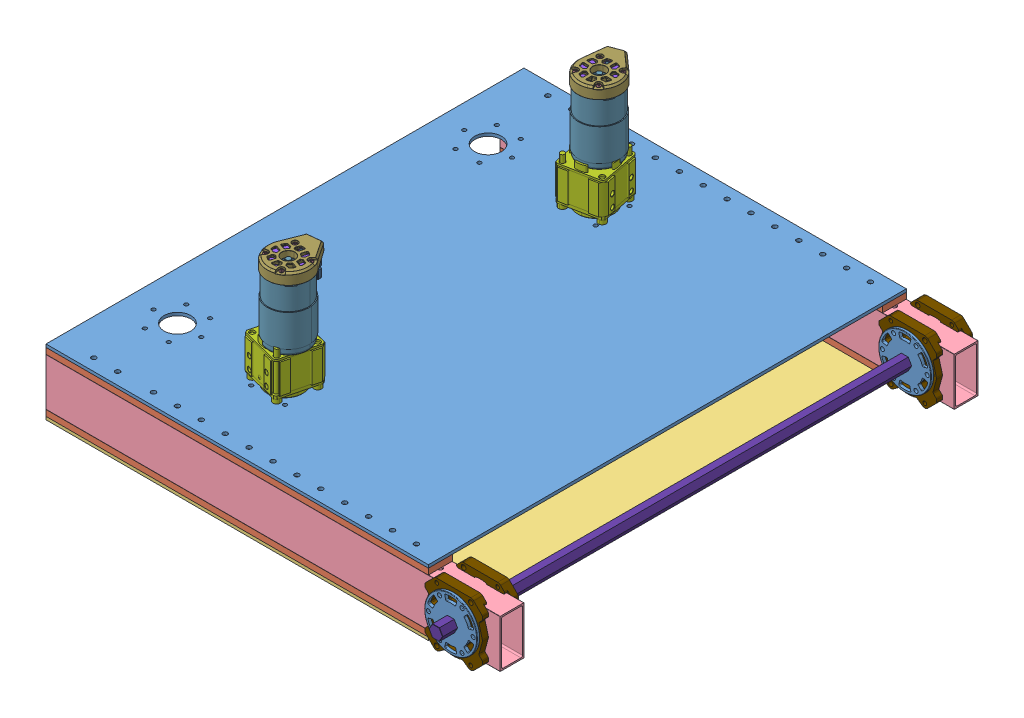
SolidWorks assembly bracket top down new shooter assembly, configuration Default. Lengths in mm.
Overall size (482.6 222.05 558.8).
61 component instances, 19 part files, 71 mates.
Components (placement in the parent):
- ShooterPlate5-1: ShooterPlate5 [Default] at (-92.3523 325.8959 643.1212) size (406.4 3.17 508)
- ThickStick-3: ThickStick [Default] at (-92.3523 262.3959 643.1212) size (406.4 6.35 25.4)
- ThickStick-1: ThickStick [Default] at (-92.3523 319.5459 643.1212) size (406.4 6.35 25.4)
- ThickStick-2: ThickStick [Default] at (-92.3523 262.3959 160.5212) size (406.4 6.35 25.4)
- ThickStick-4: ThickStick [Default] at (-92.3523 319.5459 160.5212) size (406.4 6.35 25.4)
- ShooterPlate4-1: ShooterPlate4 [Default] at (-257.4523 259.2209 643.1212) size (406.4 3.17 508)
- side-1: side [Default] at (364.8477 294.1459 147.8212) x (0 0 1) z (-1 0 0) size (25.4 50.8 482.6)
- side-2: side [Default] at (364.8477 294.1459 630.4212) x (0 0 1) z (-1 0 0) size (25.4 50.8 482.6)
- 4in hex stealth wheel-2: 4in hex stealth wheel [Default] at (72.733 290.5093 554.2466) x (0 -1 0) z (-0.5 0 0.866025) size (25.4 101.6 101.6)
  - 4in Wheel Intergreated Hub 500 HEX.STEP-1: 4in Wheel Intergreated Hub 500 HEX.STEP [Default] at origin size (25.4 92.71 92.71)
  - 4in Tread.STEP-1: 4in Tread.STEP [Default] at origin size (25.4 101.6 101.6)
- 4in hex stealth wheel-3: 4in hex stealth wheel [Default] at (72.7256 290.5093 224.0405) x (0 -1 0) z (0.194202 0 0.980962) size (25.4 101.6 101.6)
  - 4in Wheel Intergreated Hub 500 HEX.STEP-1: 4in Wheel Intergreated Hub 500 HEX.STEP [Default] at origin size (25.4 92.71 92.71)
  - 4in Tread.STEP-1: 4in Tread.STEP [Default] at origin size (25.4 101.6 101.6)
- 4-1 Banebots-1: 4-1 Banebots [Default] at (72.7475 371.6159 224.0202) x (-0.194202 0 -0.980962) z (0 -1 0) size (47.62 47.62 76.19)
- 4-1 Banebots-2: 4-1 Banebots [Default] at (72.7467 371.6159 554.2209) x (-0.969356 0 -0.245662) z (0 -1 0) size (47.62 47.62 76.19)
- 775pro.step-1: 775pro.step [Default] at (71.7936 373.6479 219.2017) x (-0.934395 0 0.356239) z (0 -1 0) size (44.99 55.15 90.45)
  - 217-6457-000 Rev2.step-1: 217-6457-000 Rev2.step [Default] at (0 0 -66.1) x (1 0 0) z (0 1 0) size (44.99 33.26 55.15)
    - 217-6457-900 Rev1.step-1: 217-6457-900 Rev1.step [Default] at (0 5.3622 0) x (-1 0 0.000693) z (0.000693 0 1) size (41.5 28.13 51.51)
      - 217-6457-901 Rev3_Instruction Config.step-1: 217-6457-901 Rev3_Instruction Config.step [Default] at origin size (41.5 2.36 51.5)
      - 30-45BBS Rev1_SHORTENED CONTACT.step-1: 30-45BBS Rev1_SHORTENED CONTACT.step [Default] at (3.95 14.4494 26.711) x (0 1 0) z (0 0 -1) size (26 3.6 2)
      - 30-45BBS Rev1_SHORTENED CONTACT.step-2: 30-45BBS Rev1_SHORTENED CONTACT.step [Default] at (-3.9748 14.4494 26.711) x (0 1 0) z (0 0 -1) size (26 3.6 2)
      - PA45XX-X Rev1.step-1: PA45XX-X Rev1.step [Default] at (-8.4198 2.3622 73.1531) x (0 1 0) z (-1 0 0) size (24.71 8.41 8.41)
      - PA45XX-X Rev1.step-2: PA45XX-X Rev1.step [Default] at (-0.495 2.3622 73.1531) x (0 1 0) z (-1 0 0) size (24.71 8.41 8.41)
    - 217-6457-001 Rev4.step-1: 217-6457-001 Rev4.step [Default] at origin size (41.49 7.8 41.49)
    - 217-6457-002 Rev7.step-1: 217-6457-002 Rev7.step [Default] at (0 0.05 0) size (44.99 11.5 55.15)
    - 217-9191-008 Rev1.step-1: 217-9191-008 Rev1.step [Default] at (81.4247 7.8 32.3804) x (-0.560945 0 -0.827853) z (0 1 0) size (4.2 4.2 11.81)
    - 217-9191-008 Rev1.step-2: 217-9191-008 Rev1.step [Default] at (32.3804 7.8 -81.4247) x (-0.827853 0 0.560945) z (0 1 0) size (4.2 4.2 11.81)
    - 217-9191-008 Rev1.step-3: 217-9191-008 Rev1.step [Default] at (-81.4247 7.8 -32.3804) x (0.560945 0 0.827853) z (0 1 0) size (4.2 4.2 11.81)
    - 217-9191-008 Rev1.step-4: 217-9191-008 Rev1.step [Default] at (-32.3804 7.8 81.4247) x (0.827853 0 -0.560945) z (0 1 0) size (4.2 4.2 11.81)
  - 217-4347-000 Rev2.step-1: 217-4347-000 Rev2.step [Default] x (0 0 -1) z (-1 0 0) size (88 44.3 44.3)
- 775pro.step-2: 775pro.step [Default] at (77.5101 373.6479 555.4281) x (-0.994351 0 0.106139) z (0 -1 0) size (44.99 55.15 90.45)
  - 217-6457-000 Rev2.step-1: 217-6457-000 Rev2.step [Default] at (0 0 -66.1) x (1 0 0) z (0 1 0) size (44.99 33.26 55.15)
    - 217-6457-900 Rev1.step-1: 217-6457-900 Rev1.step [Default] at (0 5.3622 0) x (-1 0 0.000693) z (0.000693 0 1) size (41.5 28.13 51.51)
      - 217-6457-901 Rev3_Instruction Config.step-1: 217-6457-901 Rev3_Instruction Config.step [Default] at origin size (41.5 2.36 51.5)
      - 30-45BBS Rev1_SHORTENED CONTACT.step-1: 30-45BBS Rev1_SHORTENED CONTACT.step [Default] at (3.95 14.4494 26.711) x (0 1 0) z (0 0 -1) size (26 3.6 2)
      - 30-45BBS Rev1_SHORTENED CONTACT.step-2: 30-45BBS Rev1_SHORTENED CONTACT.step [Default] at (-3.9748 14.4494 26.711) x (0 1 0) z (0 0 -1) size (26 3.6 2)
      - PA45XX-X Rev1.step-1: PA45XX-X Rev1.step [Default] at (-8.4198 2.3622 73.1531) x (0 1 0) z (-1 0 0) size (24.71 8.41 8.41)
      - PA45XX-X Rev1.step-2: PA45XX-X Rev1.step [Default] at (-0.495 2.3622 73.1531) x (0 1 0) z (-1 0 0) size (24.71 8.41 8.41)
    - 217-6457-001 Rev4.step-1: 217-6457-001 Rev4.step [Default] at origin size (41.49 7.8 41.49)
    - 217-6457-002 Rev7.step-1: 217-6457-002 Rev7.step [Default] at (0 0.05 0) size (44.99 11.5 55.15)
    - 217-9191-008 Rev1.step-1: 217-9191-008 Rev1.step [Default] at (81.4247 7.8 32.3804) x (-0.560945 0 -0.827853) z (0 1 0) size (4.2 4.2 11.81)
    - 217-9191-008 Rev1.step-2: 217-9191-008 Rev1.step [Default] at (32.3804 7.8 -81.4247) x (-0.827853 0 0.560945) z (0 1 0) size (4.2 4.2 11.81)
    - 217-9191-008 Rev1.step-3: 217-9191-008 Rev1.step [Default] at (-81.4247 7.8 -32.3804) x (0.560945 0 0.827853) z (0 1 0) size (4.2 4.2 11.81)
    - 217-9191-008 Rev1.step-4: 217-9191-008 Rev1.step [Default] at (-32.3804 7.8 81.4247) x (0.827853 0 -0.560945) z (0 1 0) size (4.2 4.2 11.81)
  - 217-4347-000 Rev2.step-1: 217-4347-000 Rev2.step [Default] x (0 0 -1) z (-1 0 0) size (88 44.3 44.3)
- 4in hex shaft-1: 4in hex shaft [Default] at (72.7477 330.8489 224.0212) x (0.752436 0 -0.658665) z (0 -1 0) size (14.66 12.7 101.6)
- 4in hex shaft-2: 4in hex shaft [Default] at (72.7477 330.8489 554.2212) x (-0.969356 0 -0.245662) z (0 -1 0) size (14.66 12.7 101.6)
- am-2986 FR8ZZ Hex Bearing.step-1: am-2986 FR8ZZ Hex Bearing.step [Default] at (72.7477 255.9925 554.2212) x (0.969356 0 0.245662) z (0 1 0) size (31.12 31.12 7.93)
- am-2986 FR8ZZ Hex Bearing.step-2: am-2986 FR8ZZ Hex Bearing.step [Default] at (72.7477 322.6675 554.2212) x (1 0 0) z (0 1 0) size (31.12 31.12 7.93)
- am-2986 FR8ZZ Hex Bearing.step-3: am-2986 FR8ZZ Hex Bearing.step [Default] at (72.7477 322.6675 224.0212) x (0.194202 0 0.980962) z (0 1 0) size (31.12 31.12 7.93)
- am-2986 FR8ZZ Hex Bearing.step-4: am-2986 FR8ZZ Hex Bearing.step [Default] at (72.7477 255.9925 224.0212) x (0.946639 0 0.322297) z (0 1 0) size (31.12 31.12 7.93)
- shooteraxle-1: shooteraxle [Default] at (347.36 295.7842 109.7212) size (14.66 12.7 558.8)
- VersaBlock V2 (217-6111).step-1: VersaBlock V2 (217-6111).step [Default] at (347.3674 295.7969 131.9462) x (1 0 0) z (0 0 -1) size (61.04 66.67 9.53)
- VersaBlock V2 (217-6111).step-2: VersaBlock V2 (217-6111).step [Default] at (347.3674 295.7969 614.5462) x (1 0 0) z (0 0 -1) size (61.04 66.67 9.53)
- VersaBlock V2 (217-6111).step-3: VersaBlock V2 (217-6111).step [Default] at (347.3674 295.7969 646.2962) x (-1 0 0) z (0 0 1) size (61.04 66.67 9.53)
- VersaBlock V2 (217-6111).step-4: VersaBlock V2 (217-6111).step [Default] at (347.3674 295.7969 163.6962) x (-1 0 0) z (0 0 1) size (61.04 66.67 9.53)
- 1_2” Hex Bore Aluminum VersaHub (217-2592).step-1: 1_2” Hex Bore Aluminum VersaHub (217-2592).step [Default] at (347.3674 295.7969 138.2962) x (0 0 -1) z (0.866025 -0.5 0) size (12.7 55.88 55.88)
- 1_2” Hex Bore Aluminum VersaHub (217-2592).step-2: 1_2” Hex Bore Aluminum VersaHub (217-2592).step [Default] at (347.3674 295.7969 157.3462) x (0 0 1) z (-0.866025 -0.5 0) size (12.7 55.88 55.88)
- 1_2” Hex Bore Aluminum VersaHub (217-2592).step-3: 1_2” Hex Bore Aluminum VersaHub (217-2592).step [Default] at (347.3674 295.7969 620.8962) x (0 0 -1) z (0.866025 0.5 0) size (12.7 55.88 55.88)
- 1_2” Hex Bore Aluminum VersaHub (217-2592).step-4: 1_2” Hex Bore Aluminum VersaHub (217-2592).step [Default] at (347.3674 295.7969 639.9462) x (0 0 1) z (-0.866025 0.5 0) size (12.7 55.88 55.88)
Mates (geometry in assembly coordinates):
- Coincident2: coincident aligned: plane of ShooterPlate5-1 through (-92.3523 329.0709 643.1212) normal (-1 0 0); plane of side-2 through (-92.3523 319.2919 642.8672) normal (-1 0 0)
- Coincident3: coincident aligned: plane of ShooterPlate5-1 through (-92.3523 329.0709 643.1212) normal (0 0 1); plane of side-2 through (390.2477 319.2919 643.1212) normal (0 0 1)
- Coincident4: coincident anti-aligned: plane of ShooterPlate5-1 through (-92.3523 325.8959 643.1212) normal (0 -1 0); plane of ThickStick-1 through (-92.3523 325.8959 643.1212) normal (0 1 0)
- Coincident5: coincident aligned: plane of ShooterPlate5-1 through (314.0477 329.0709 643.1212) normal (1 0 0); plane of ThickStick-1 through (314.0477 325.8959 643.1212) normal (1 0 0)
- Coincident6: coincident aligned: plane of ShooterPlate5-1 through (-92.3523 329.0709 643.1212) normal (0 0 1); plane of ThickStick-1 through (-92.3523 325.8959 643.1212) normal (0 0 1)
- Coincident7: coincident anti-aligned: plane of ThickStick-1 through (-92.3523 319.5459 643.1212) normal (0 -1 0); plane of side-2 through (390.2477 319.5459 617.9752) normal (0 1 0)
- Coincident8: coincident anti-aligned: plane of ThickStick-3 through (-92.3523 268.7459 643.1212) normal (0 1 0); plane of side-2 through (390.2477 268.7459 642.8672) normal (0 -1 0)
- Coincident9: coincident aligned: plane of ThickStick-3 through (-92.3523 268.7459 643.1212) normal (0 0 1); plane of side-2 through (390.2477 319.2919 643.1212) normal (0 0 1)
- Coincident11: coincident aligned: plane of ThickStick-1 through (-92.3523 325.8959 643.1212) normal (-1 0 0); plane of ThickStick-3 through (-92.3523 268.7459 643.1212) normal (-1 0 0)
- Coincident12: coincident anti-aligned: plane of ThickStick-3 through (-92.3523 262.3959 643.1212) normal (0 -1 0); plane of ShooterPlate4-1 through (-257.4523 262.3959 643.1212) normal (0 1 0)
- Coincident13: coincident aligned: plane of ShooterPlate5-1 through (-92.3523 329.0709 643.1212) normal (0 0 1); plane of ShooterPlate4-1 through (-257.4523 262.3959 643.1212) normal (0 0 1)
- Coincident14: coincident aligned: plane of ThickStick-3 through (314.0477 268.7459 643.1212) normal (1 0 0); plane of ShooterPlate4-1 through (314.0477 262.3959 643.1212) normal (1 0 0)
- Coincident15: coincident anti-aligned: plane of ShooterPlate5-1 through (-92.3523 325.8959 643.1212) normal (0 -1 0); plane of ThickStick-4 through (-92.3523 325.8959 160.5212) normal (0 1 0)
- Coincident16: coincident aligned: plane of ShooterPlate5-1 through (-92.3523 329.0709 643.1212) normal (-1 0 0); plane of ThickStick-4 through (-92.3523 325.8959 160.5212) normal (-1 0 0)
- Coincident17: coincident anti-aligned: plane of ThickStick-4 through (-92.3523 319.5459 160.5212) normal (0 -1 0); plane of side-1 through (390.2477 319.5459 135.3752) normal (0 1 0)
- Coincident18: coincident aligned: plane of ShooterPlate5-1 through (-92.3523 329.0709 135.1212) normal (0 0 -1); plane of ThickStick-4 through (-92.3523 325.8959 135.1212) normal (0 0 -1)
- Coincident19: coincident aligned: plane of ThickStick-4 through (-92.3523 325.8959 135.1212) normal (0 0 -1); plane of side-1 through (390.2477 268.9999 135.1212) normal (0 0 -1)
- Coincident20: coincident aligned: plane of ThickStick-4 through (-92.3523 325.8959 160.5212) normal (-1 0 0); plane of side-1 through (-92.3523 319.2919 160.2672) normal (-1 0 0)
- Coincident21: coincident anti-aligned: plane of ThickStick-2 through (-92.3523 262.3959 160.5212) normal (0 -1 0); plane of ShooterPlate4-1 through (-257.4523 262.3959 643.1212) normal (0 1 0)
- Coincident22: coincident aligned: plane of ThickStick-2 through (-92.3523 268.7459 135.1212) normal (0 0 -1); plane of side-1 through (390.2477 268.9999 135.1212) normal (0 0 -1)
- Coincident23: coincident aligned: plane of ShooterPlate5-1 through (-92.3523 329.0709 643.1212) normal (-1 0 0); plane of ThickStick-2 through (-92.3523 268.7459 160.5212) normal (-1 0 0)
- Concentric10: concentric anti-aligned: cylinder of ShooterPlate5-1 through (72.7477 325.8959 224.0212) axis (0 1 0) radius 14.2875; cylinder of am-2986 FR8ZZ Hex Bearing.step-3 through (72.7477 330.5949 224.0212) axis (0 -1 0) radius 14.2875
- Coincident39: coincident anti-aligned: plane of ShooterPlate5-1 through (-92.3523 329.0709 643.1212) normal (0 1 0); plane of am-2986 FR8ZZ Hex Bearing.step-3 through (75.4607 329.0709 237.7252) normal (0 -1 0)
- Concentric11: concentric anti-aligned: cylinder of ShooterPlate5-1 through (72.7477 325.8959 554.2212) axis (0 1 0) radius 14.2875; cylinder of am-2986 FR8ZZ Hex Bearing.step-2 through (72.7477 330.5949 554.2212) axis (0 -1 0) radius 14.2875
- Coincident40: coincident anti-aligned: plane of ShooterPlate5-1 through (-92.3523 329.0709 643.1212) normal (0 1 0); plane of am-2986 FR8ZZ Hex Bearing.step-2 through (86.7177 329.0709 554.2212) normal (0 -1 0)
- Concentric12: concentric anti-aligned: cylinder of ShooterPlate4-1 through (72.7477 259.2209 554.2212) axis (0 1 0) radius 14.2875; cylinder of am-2986 FR8ZZ Hex Bearing.step-1 through (72.7477 263.9199 554.2212) axis (0 -1 0) radius 14.2875
- Coincident41: coincident anti-aligned: plane of ShooterPlate4-1 through (-257.4523 262.3959 643.1212) normal (0 1 0); plane of am-2986 FR8ZZ Hex Bearing.step-1 through (86.2896 262.3959 557.6531) normal (0 -1 0)
- Concentric13: concentric anti-aligned: cylinder of ShooterPlate4-1 through (72.7477 259.2209 224.0212) axis (0 1 0) radius 14.2875; cylinder of am-2986 FR8ZZ Hex Bearing.step-4 through (72.7477 263.9199 224.0212) axis (0 -1 0) radius 14.2875
- Coincident42: coincident anti-aligned: plane of ShooterPlate4-1 through (-257.4523 262.3959 643.1212) normal (0 1 0); plane of am-2986 FR8ZZ Hex Bearing.step-4 through (85.9723 262.3959 228.5236) normal (0 -1 0)
- Coincident44: coincident anti-aligned: plane of 4-1 Banebots-1 through (67.2306 330.8559 228.8507) normal (-0.980962 0 0.194202); plane of am-2986 FR8ZZ Hex Bearing.step-3 through (67.2306 330.5949 228.8507) normal (0.980962 0 -0.194202)
- Coincident53: coincident anti-aligned: plane of 4in hex shaft-2 through (67.6339 229.2489 559.4759) normal (-0.245662 0 0.969356); plane of am-2986 FR8ZZ Hex Bearing.step-1 through (74.7416 263.9199 561.2772) normal (0.245662 0 -0.969356)
- Coincident54: coincident anti-aligned: plane of 4in hex shaft-2 through (65.6401 229.2489 552.4199) normal (-0.962318 0 0.271928); plane of am-2986 FR8ZZ Hex Bearing.step-1 through (67.6339 263.9199 559.4759) normal (0.962318 0 -0.271928)
- Tangent9: tangent: plane of assembly; face of 4-1 Banebots-2; plane of 4in hex shaft-2 through (72.7477 330.8489 554.2212) normal (0 1 0)
- Coincident55: coincident aligned: plane of 4-1 Banebots-2 through (65.6401 330.8559 552.4199) normal (-0.716656 0 -0.697427); plane of 4in hex shaft-2 through (70.7538 229.2489 547.1651) normal (-0.716656 0 -0.697427)
- Coincident56: coincident aligned: plane of 4-1 Banebots-2 through (70.7538 330.8559 547.1651) normal (0.245662 0 -0.969356); plane of 4in hex shaft-2 through (77.8615 229.2489 548.9664) normal (0.245662 0 -0.969356)
- Tangent10: tangent: plane of assembly; face of 4-1 Banebots-2; plane of am-2986 FR8ZZ Hex Bearing.step-2 through (88.3052 330.5949 554.2212) normal (0 1 0)
- Tangent11: tangent: plane of assembly; face of 4-1 Banebots-1; plane of 4in hex shaft-1 through (72.7477 330.8489 224.0212) normal (0 1 0)
- Coincident57: coincident aligned: plane of 4-1 Banebots-1 through (65.8066 330.8559 221.658) normal (-0.658665 0 -0.752436); plane of 4in hex shaft-1 through (71.3238 229.2489 216.8284) normal (-0.658665 0 -0.752436)
- Coincident58: coincident aligned: plane of 4-1 Banebots-1 through (67.2306 330.8559 228.8507) normal (-0.980962 0 0.194202); plane of 4in hex shaft-1 through (65.8066 229.2489 221.658) normal (-0.980962 0 0.194202)
- Tangent12: tangent: plane of assembly; face of 4-1 Banebots-1; plane of am-2986 FR8ZZ Hex Bearing.step-3 through (75.769 330.5949 239.2825) normal (0 1 0)
- Coincident60: coincident anti-aligned: plane of 4in hex shaft-1 through (79.6888 229.2489 226.3843) normal (0.980962 0 -0.194202); plane of am-2986 FR8ZZ Hex Bearing.step-4 through (78.2648 263.9199 219.1916) normal (-0.980962 0 0.194202)
- Coincident61: coincident anti-aligned: plane of 4in hex shaft-1 through (74.1717 229.2489 231.2139) normal (0.658665 0 0.752436); plane of am-2986 FR8ZZ Hex Bearing.step-4 through (79.6888 263.9199 226.3843) normal (-0.658665 0 -0.752436)
- Coincident62: coincident anti-aligned: plane of 4in hex stealth wheel-3/4in Wheel Intergreated Hub 500 HEX.STEP-1 through (71.296 304.4334 216.819) normal (-0.322297 0 0.946639); plane of 4in hex shaft-1 through (78.2648 229.2489 219.1916) normal (0.322297 0 -0.946639)
- Coincident63: coincident anti-aligned: plane of 4in hex stealth wheel-3/4in Wheel Intergreated Hub 500 HEX.STEP-1 through (78.2648 304.4334 219.1916) normal (-0.980962 0 0.194202); plane of 4in hex shaft-1 through (79.6888 229.2489 226.3843) normal (0.980962 0 -0.194202)
- Coincident72: coincident anti-aligned: plane of side-2 through (390.2477 319.2919 643.1212) normal (0 0 1); plane of VersaBlock V2 (217-6111).step-3 through (347.3674 295.7969 643.1212) normal (0 0 -1)
- Coincident73: coincident anti-aligned: plane of side-2 through (390.2477 268.7459 642.8672) normal (0 -1 0); plane of VersaBlock V2 (217-6111).step-3 through (316.8493 268.7459 722.6131) normal (0 1 0)
- Tangent13: tangent aligned: cylinder of side-2 through (345.7977 295.9239 643.1212) axis (0 0 -1) radius 12.7; cylinder of VersaBlock V2 (217-6111).step-3 through (347.3674 295.7969 604.2621) axis (0 0 1) radius 14.2748
- Coincident74: coincident anti-aligned: plane of side-2 through (390.2477 268.9999 617.7212) normal (0 0 -1); plane of VersaBlock V2 (217-6111).step-2 through (347.3674 295.7969 617.7212) normal (0 0 1)
- Coincident75: coincident anti-aligned: plane of side-2 through (390.2477 268.7459 642.8672) normal (0 -1 0); plane of VersaBlock V2 (217-6111).step-2 through (377.8855 268.7459 538.2292) normal (0 1 0)
- Concentric24: concentric anti-aligned: cylinder of VersaBlock V2 (217-6111).step-2 through (365.4542 323.1543 620.8962) axis (0 0 1) radius 2.0193; cylinder of VersaBlock V2 (217-6111).step-3 through (365.4542 323.1543 639.9462) axis (0 0 -1) radius 2.4892
- Coincident76: coincident anti-aligned: plane of side-1 through (390.2477 268.9999 135.1212) normal (0 0 -1); plane of VersaBlock V2 (217-6111).step-1 through (347.3674 295.7969 135.1212) normal (0 0 1)
- Coincident77: coincident anti-aligned: plane of side-1 through (390.2477 268.7459 160.2672) normal (0 -1 0); plane of VersaBlock V2 (217-6111).step-1 through (377.8855 268.7459 55.6292) normal (0 1 0)
- Tangent14: tangent aligned: cylinder of side-1 through (345.7977 295.9239 160.5212) axis (0 0 -1) radius 12.7; cylinder of VersaBlock V2 (217-6111).step-1 through (347.3674 295.7969 173.9802) axis (0 0 -1) radius 14.2748
- Coincident78: coincident anti-aligned: plane of side-1 through (390.2477 268.7459 160.2672) normal (0 -1 0); plane of VersaBlock V2 (217-6111).step-4 through (316.8493 268.7459 240.0131) normal (0 1 0)
- Coincident79: coincident anti-aligned: plane of side-1 through (390.2477 319.2919 160.5212) normal (0 0 1); plane of VersaBlock V2 (217-6111).step-4 through (347.3674 295.7969 160.5212) normal (0 0 -1)
- Concentric26: concentric anti-aligned: cylinder of VersaBlock V2 (217-6111).step-1 through (365.4542 323.1543 138.2962) axis (0 0 1) radius 2.0193; cylinder of VersaBlock V2 (217-6111).step-4 through (365.4542 323.1543 157.3462) axis (0 0 -1) radius 2.4892
- Coincident80: coincident anti-aligned: plane of VersaBlock V2 (217-6111).step-3 through (359.2736 316.4191 649.4712) normal (0 0 1); plane of 1_2” Hex Bore Aluminum VersaHub (217-2592).step-4 through (354.5148 308.1766 649.4712) normal (0 0 -1)
- Concentric30: concentric aligned: cylinder of VersaBlock V2 (217-6111).step-3 through (335.4611 316.4191 649.4712) axis (0 0 1) radius 1.7272; cylinder of 1_2” Hex Bore Aluminum VersaHub (217-2592).step-4 through (335.4611 316.4191 566.8528) axis (0 0 1) radius 2.15
- Concentric31: concentric aligned: cylinder of VersaBlock V2 (217-6111).step-3 through (359.2736 316.4191 649.4712) axis (0 0 1) radius 1.7272; cylinder of 1_2” Hex Bore Aluminum VersaHub (217-2592).step-4 through (359.2736 316.4191 566.8528) axis (0 0 1) radius 2.15
- Coincident82: coincident anti-aligned: plane of VersaBlock V2 (217-6111).step-1 through (335.4611 316.4191 128.7712) normal (0 0 -1); plane of 1_2” Hex Bore Aluminum VersaHub (217-2592).step-1 through (354.5148 308.1766 128.7712) normal (0 0 1)
- Concentric32: concentric aligned: cylinder of VersaBlock V2 (217-6111).step-1 through (335.4611 316.4191 128.7712) axis (0 0 -1) radius 1.7272; cylinder of 1_2” Hex Bore Aluminum VersaHub (217-2592).step-1 through (335.4611 316.4191 211.3895) axis (0 0 -1) radius 2.15
- Concentric33: concentric aligned: cylinder of VersaBlock V2 (217-6111).step-1 through (359.2736 316.4191 128.7712) axis (0 0 -1) radius 1.7272; cylinder of 1_2” Hex Bore Aluminum VersaHub (217-2592).step-1 through (359.2736 316.4191 211.3895) axis (0 0 -1) radius 2.15
- Coincident83: coincident anti-aligned: plane of VersaBlock V2 (217-6111).step-4 through (359.2736 316.4191 166.8712) normal (0 0 1); plane of 1_2” Hex Bore Aluminum VersaHub (217-2592).step-2 through (340.2199 308.1766 166.8712) normal (0 0 -1)
- Concentric35: concentric aligned: cylinder of VersaBlock V2 (217-6111).step-4 through (359.2736 316.4191 166.8712) axis (0 0 1) radius 1.7272; cylinder of 1_2” Hex Bore Aluminum VersaHub (217-2592).step-2 through (359.2736 316.4191 84.2528) axis (0 0 1) radius 2.15
- Concentric36: concentric aligned: cylinder of VersaBlock V2 (217-6111).step-4 through (335.4611 316.4191 166.8712) axis (0 0 1) radius 1.7272; cylinder of 1_2” Hex Bore Aluminum VersaHub (217-2592).step-2 through (335.4611 316.4191 84.2528) axis (0 0 1) radius 2.15
- Coincident84: coincident anti-aligned: plane of VersaBlock V2 (217-6111).step-2 through (335.4611 316.4191 611.3712) normal (0 0 -1); plane of 1_2” Hex Bore Aluminum VersaHub (217-2592).step-3 through (340.2199 308.1766 611.3712) normal (0 0 1)
- Concentric37: concentric aligned: cylinder of VersaBlock V2 (217-6111).step-2 through (359.2736 316.4191 611.3712) axis (0 0 -1) radius 1.7272; cylinder of 1_2” Hex Bore Aluminum VersaHub (217-2592).step-3 through (359.2736 316.4191 693.9895) axis (0 0 -1) radius 2.15
- Concentric38: concentric aligned: cylinder of VersaBlock V2 (217-6111).step-2 through (335.4611 316.4191 611.3712) axis (0 0 -1) radius 1.7272; cylinder of 1_2” Hex Bore Aluminum VersaHub (217-2592).step-3 through (335.4611 316.4191 693.9895) axis (0 0 -1) radius 2.15
- Coincident85: coincident anti-aligned: plane of shooteraxle-1 through (351.0262 289.4342 668.5212) normal (0 -1 0); plane of 1_2” Hex Bore Aluminum VersaHub (217-2592).step-4 through (343.6939 289.4342 639.9462) normal (0 1 0)
- Coincident86: coincident anti-aligned: plane of shooteraxle-1 through (343.6939 289.4342 668.5212) normal (-0.866025 -0.5 0); plane of 1_2” Hex Bore Aluminum VersaHub (217-2592).step-4 through (340.0204 295.7969 639.9462) normal (0.866025 0.5 0)
- Distance2: distance = 25.4 mm aligned: plane of shooteraxle-1 through (347.36 295.7842 668.5212) normal (0 0 1); plane of side-2 through (390.2477 319.2919 643.1212) normal (0 0 1)
